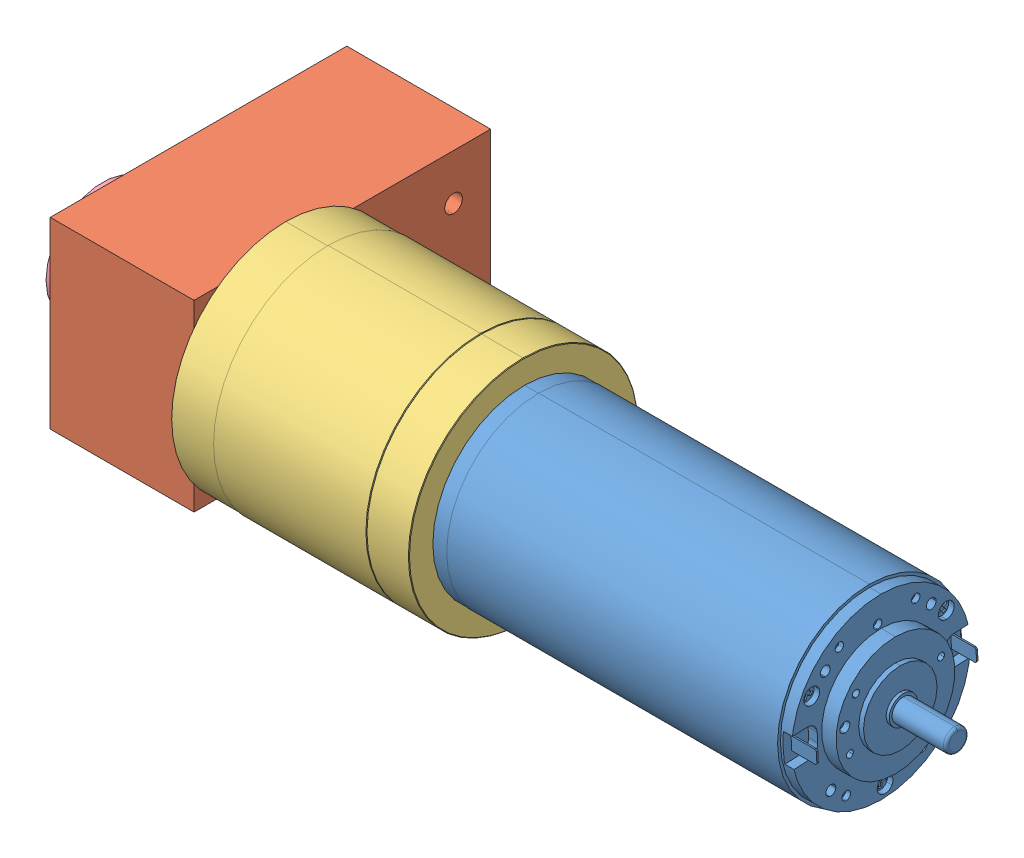
SolidWorks assembly VerticalMotorAssembly, configuration Default. Lengths in mm.
Overall size (302 81 112.87).
4 component instances, 4 part files, 7 mates.
Components (placement in the parent):
- 353294_RE65_GB_250W_KL_2WE.stp-1: 353294_RE65_GB_250W_KL_2WE.stp [Default] at (-12.2671 92.7605 156.1942) size (185.5 65 65)
- MotorMounting-1: MotorMounting [Default] at (-147.0671 92.7605 156.1942) x (0 0 -1) z (1 0 0) size (104.77 64.8 50.8)
- GP81-Stage1.stp-1: GP81-Stage1.stp [Default] at (-12.2671 92.7605 156.1942) size (133.6 81 81)
- 19mm coupling-1: 19mm coupling [Default] at (-160.9671 92.7605 156.1942) x (0 0 -1) z (1 0 0) size (40 40 55)
Mates (geometry in assembly coordinates):
- Concentric1: concentric aligned: cylinder of 353294_RE65_GB_250W_KL_2WE.stp-1 through (-53.7421 92.7605 156.1942) axis (1 0 0) radius 32.5; cylinder of GP81-Stage1.stp-1 through (-152.8621 92.7605 156.1942) axis (1 0 0) radius 40.5
- Coincident1: coincident anti-aligned: plane of 353294_RE65_GB_250W_KL_2WE.stp-1 through (-12.2671 92.7605 156.1942) normal (-1 0 0); plane of GP81-Stage1.stp-1 through (-12.2671 92.7605 156.1942) normal (1 0 0)
- Concentric2: concentric anti-aligned: cylinder of MotorMounting-1 through (-96.2671 92.7605 156.1942) axis (-1 0 0) radius 25; cylinder of GP81-Stage1.stp-1 through (-152.8621 92.7605 156.1942) axis (1 0 0) radius 25
- Coincident2: coincident anti-aligned: plane of MotorMounting-1 through (-96.2671 92.7605 156.1942) normal (1 0 0); plane of GP81-Stage1.stp-1 through (-96.2671 92.7605 156.1942) normal (-1 0 0)
- Concentric3: concentric aligned: cylinder of MotorMounting-1 through (-96.2671 115.7414 133.2132) axis (-1 0 0) radius 2.5; cylinder of GP81-Stage1.stp-1 through (-73.6899 115.7414 133.2132) axis (-1 0 0) radius 2.5
- Concentric4: concentric anti-aligned: cylinder of GP81-Stage1.stp-1 through (-152.5621 92.7605 156.1942) axis (1 0 0) radius 9.5; cylinder of 19mm coupling-1 through (-105.9671 92.7605 156.1942) axis (-1 0 0) radius 9.5
- Coincident3: coincident anti-aligned: plane of GP81-Stage1.stp-1 through (-105.9671 92.7605 156.1942) normal (-1 0 0); plane of 19mm coupling-1 through (-105.9671 92.7605 156.1942) normal (1 0 0)
